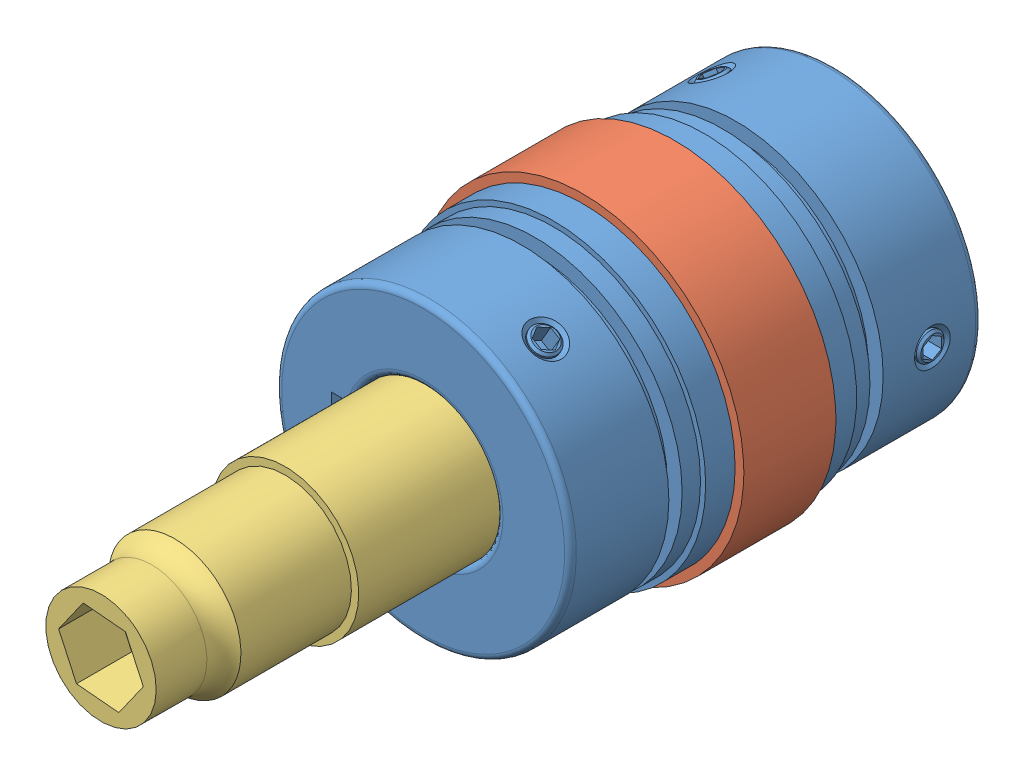
SolidWorks assembly couplerassembly, configuration Default. Lengths in mm.
Overall size (55.56 55.56 126.52).
5 component instances, 4 part files, 10 mates.
Components (placement in the parent):
- CouplerPiece-1: CouplerPiece [3565N164] at (36.8846 41.6241 29.2971) x (0 0 -1) z (1 0 0) size (34.96 52.58 52.58)
- CouplerPiece-2: CouplerPiece [3565N164] at (36.8846 41.6241 55.3321) x (0 0 1) z (-1 0 0) size (34.96 52.58 52.58)
- CouplerConnection-1: CouplerConnection [Default] at (36.8846 41.6241 34.3771) size (55.56 55.56 15.88)
- CouplerShaft-1: CouplerShaft [Default] at (36.8846 41.6241 50.7601) x (0.5719 0.820324 0) z (0 0 1) size (25.4 25.4 82.55)
- 98870A405_STEEL MACHINE KEY-1: 98870A405_STEEL MACHINE KEY [98870A405] at (24.2596 43.9741 66.6351) x (0 0 1) z (-1 0 0) (suppressed, hidden)
Mates (geometry in assembly coordinates):
- Concentric1: concentric anti-aligned: cylinder of 3565N164_HIGH-TORQUE SET SCREW FLEXIBLE SHAFT COUPLING-1 through (36.8846 41.6241 34.6311) axis (0 0 -1) radius 26.289; cylinder of 3565N164_HIGH-TORQUE SET SCREW FLEXIBLE SHAFT COUPLING-2 through (36.8846 41.6241 49.9981) axis (0 0 1) radius 26.289
- Coincident1: coincident aligned: plane of 3565N164_HIGH-TORQUE SET SCREW FLEXIBLE SHAFT COUPLING-1 through (41.7106 55.0719 34.3771) normal (1 0 0); plane of 3565N164_HIGH-TORQUE SET SCREW FLEXIBLE SHAFT COUPLING-2 through (41.7106 67.4664 50.2521) normal (1 0 0)
- Coincident2: coincident anti-aligned: plane of 3565N164_HIGH-TORQUE SET SCREW FLEXIBLE SHAFT COUPLING-1 through (36.8846 41.6241 34.3771) normal (0 0 1); plane of CouplerConnection-1 through (36.8846 41.6241 34.3771) normal (0 0 -1)
- Coincident3: coincident anti-aligned: plane of 3565N164_HIGH-TORQUE SET SCREW FLEXIBLE SHAFT COUPLING-2 through (36.8846 41.6241 50.2521) normal (0 0 -1); plane of CouplerConnection-1 through (36.8846 41.6241 50.2521) normal (0 0 1)
- Concentric4: concentric aligned: cylinder of 3565N164_HIGH-TORQUE SET SCREW FLEXIBLE SHAFT COUPLING-1 through (36.8846 41.6241 30.4185) axis (0 0 -1) radius 25.4; cylinder of CouplerConnection-1 through (36.8846 41.6241 50.2521) axis (0 0 -1) radius 27.7812
- Concentric5: concentric anti-aligned: cylinder of CouplerPiece-2 through (36.8846 41.6241 12.9991) axis (0 0 1) radius 12.5; cylinder of CouplerShaft-1 through (36.8846 41.6241 101.5601) axis (0 0 -1) radius 12.7
- Coincident5: coincident anti-aligned: circle of CouplerPiece-2; plane of CouplerShaft-1 through (36.8846 41.6241 50.7601) normal (0 0 -1)
- Coincident6: coincident anti-aligned: plane of CouplerPiece-2 through (21.0846 45.6241 12.9991) normal (1 0 0); plane of 98870A405_STEEL MACHINE KEY-1 through (23.7697 38.1272 49.0179) normal (-1 0 0)
- Coincident7: coincident anti-aligned: plane of CouplerPiece-2 through (21.0846 37.6241 12.9991) normal (0 1 0); plane of 98870A405_STEEL MACHINE KEY-1 through (23.7697 38.1272 49.0179) normal (0 -1 0)
- Coincident9: coincident aligned: plane of CouplerShaft-1 through (36.8846 41.6241 50.7601) normal (0 0 -1); plane of 98870A405_STEEL MACHINE KEY-1 through (27.4346 37.6241 50.7601) normal (0 0 -1)
